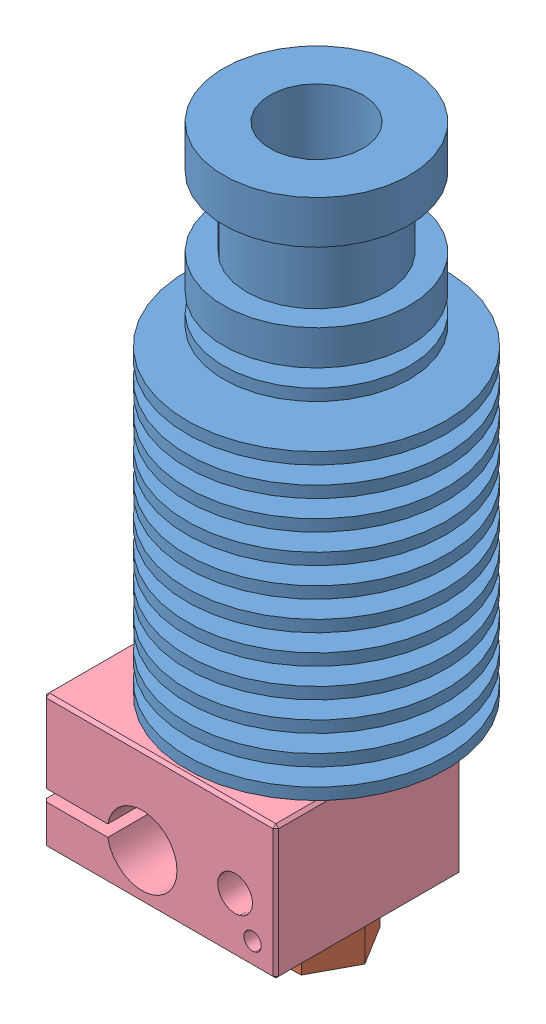
SolidWorks assembly ED3V6, configuration Valor predeterminado. Lengths in mm.
Overall size (26.65 62.8 22.3).
4 component instances, 4 part files, 0 mates.
Components (placement in the parent):
- HEATSINK-1: HEATSINK [Valor predeterminado] at origin size (22.3 42.7 22.3)
- NOZZLE 0.4-1: NOZZLE 0.4 [Valor predeterminado] at (0 -18.1 0) x (0.999537 0 -0.030412) z (0.030412 0 0.999537) size (8.08 12.5 7)
- HEATBRICK-1: HEATBRICK [Valor predeterminado] at (0 -7.6 0) x (0.965851 0 -0.259098) z (0.259098 0 0.965851) size (7 21.9 7)
- HEATERBLOCK-1: HEATERBLOCK [Valor predeterminado] at (-5.5 -15.1 0) size (20 11.5 16)
